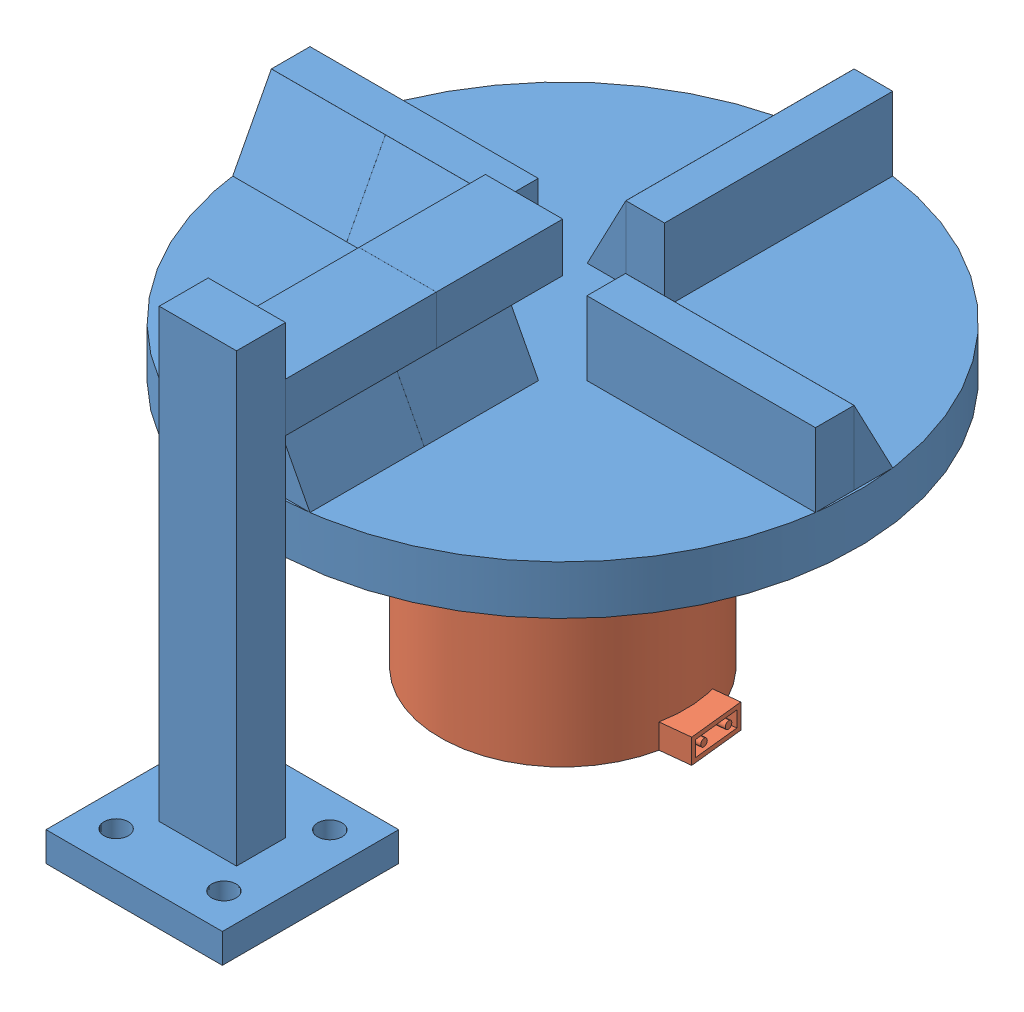
SolidWorks assembly Assem1, configuration Default. Lengths in mm.
Overall size (120 97.09 147.48).
2 component instances, 2 part files, 2 mates.
Components (placement in the parent):
- bar-1: bar [Default] at (5.4738 79.0495 125.877) size (120 97.09 147.48)
- Part1-1: Part1 [Default] at (5.4738 28.0495 125.877) x (0.994239 0 -0.107184) z (0.107184 0 0.994239) size (54.93 55 50)
Mates (geometry in assembly coordinates):
- Concentric1: concentric aligned: cylinder of bar-1 through (5.4738 83.0495 125.877) axis (0 -1 0) radius 1.5; cylinder of Part1-1 through (5.4738 83.0495 125.877) axis (0 -1 0) radius 1.5
- Coincident1: coincident anti-aligned: plane of bar-1 through (5.4738 83.0495 125.877) normal (0 -1 0); plane of Part1-1 through (5.4738 83.0495 125.877) normal (0 1 0)
